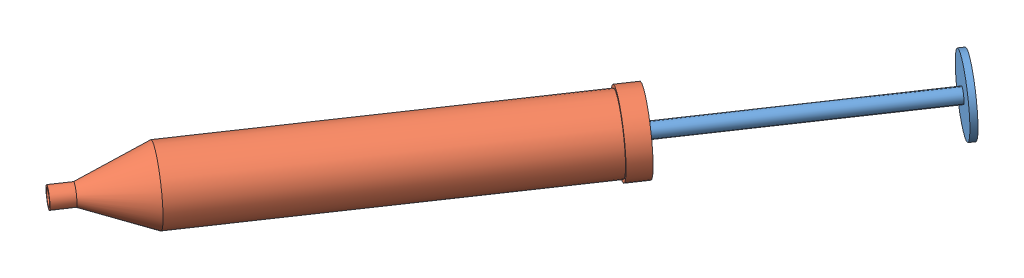
SolidWorks assembly Syringe Assembly, configuration Default. Lengths in mm.
Overall size (238.74 54.97 302.05).
2 component instances, 2 part files, 2 mates.
Components (placement in the parent):
- Syringe Piston-1: Syringe Piston [Default] at (-31.9339 131.2985 173.9451) x (-0.765977 0.33104 -0.551082) z (0.251005 0.943188 0.217698) size (34.88 206 34.88)
- Syringe-1: Syringe [Default] at (-37.5576 131.0284 181.5995) x (-0.761165 -0.309142 -0.570139) z (0.265238 -0.950591 0.161325) size (36.56 221.26 36.56)
Mates (geometry in assembly coordinates):
- Concentric1: concentric aligned: cylinder of Syringe Piston-1 through (-49.6891 130.4457 198.1117) axis (0.591841 0.028427 -0.805553) radius 16.5; circle of Syringe-1
- LimitDistance1: limit distance = 135.7131 mm aligned: plane of Syringe-1 through (-130.0097 126.5877 307.4357) normal (-0.591841 -0.028427 0.805553); plane of Syringe Piston-1 through (-49.6891 130.4457 198.1117) normal (-0.591841 -0.028427 0.805553)
